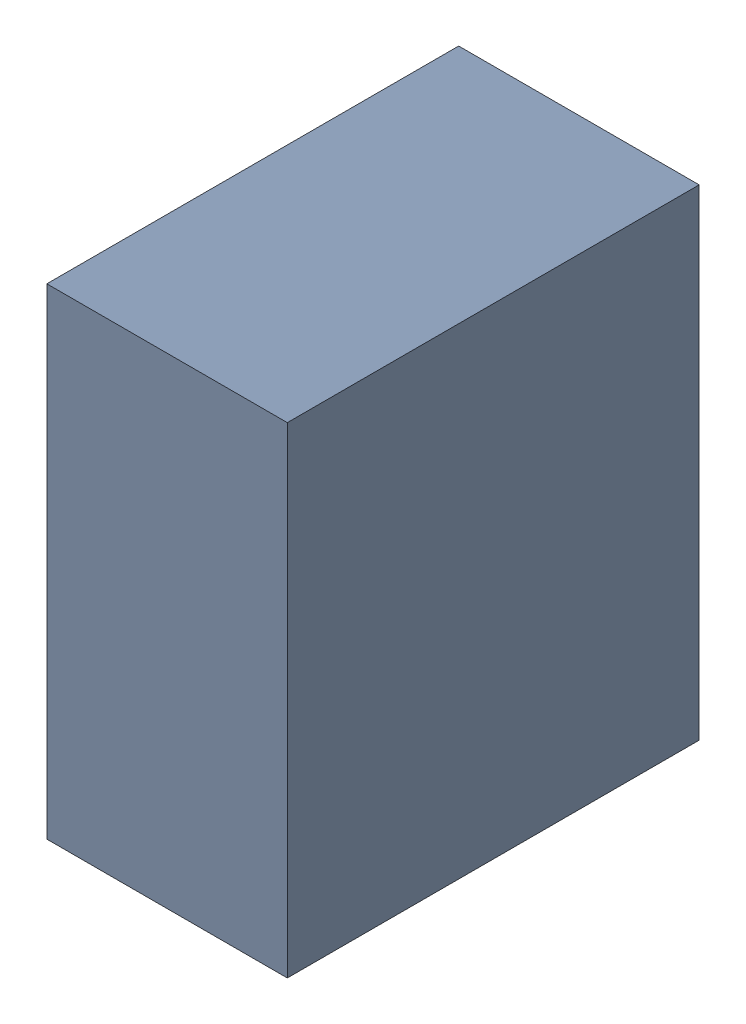
SolidWorks assembly U6Kanaloa_v2.0.0_GPIO_b, configuration Default. Lengths in mm.
Overall size (5.6 10.5 1.75).
2 component instances, 1 part files, 0 mates.
Components (placement in the parent):
- 352878160-1: 352878160 [Default] at (72.898 50.419 0.25) size (0.51 1.02 0.87)
  - Extruded_4-1: Extruded_4 [Default] at origin size (0.51 1.02 0.87)
